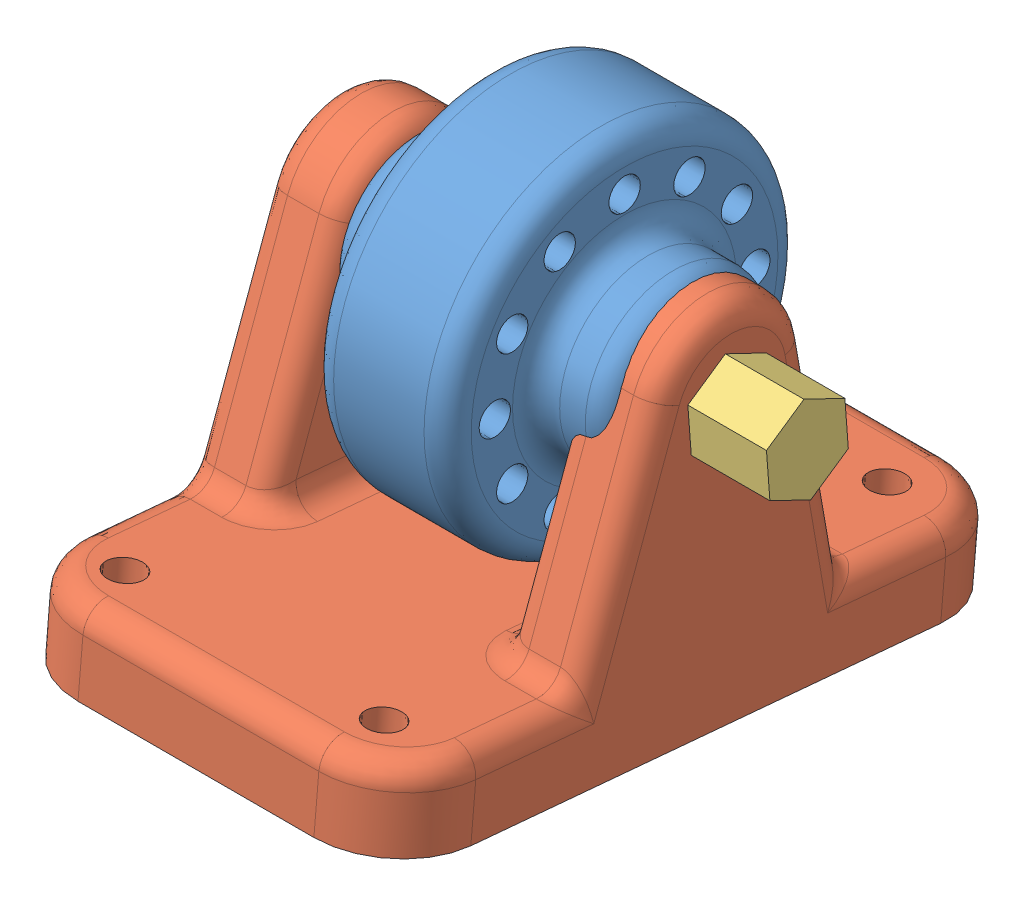
SolidWorks assembly Assem2, configuration Default. Lengths in mm.
Overall size (60 61.02 83.77).
3 component instances, 3 part files, 4 mates.
Components (placement in the parent):
- t7-1: t7 [Default] at (-20.7572 24.5909 48.9887) size (36 45 45)
- T-1: T [Default] at (-15.0072 -6.7591 91.7512) x (0 -0.089597 -0.995978) z (1 0 0) size (80 45.68 50)
- t12-1: t12 [Default] at (19.9928 24.5909 48.9887) x (0 -0.901395 0.432998) z (-1 0 0) size (10 11.55 60)
Mates (geometry in assembly coordinates):
- Concentric1: concentric anti-aligned: circle of t7-1; circle of T-1
- Coincident2: coincident anti-aligned: plane of t7-1 through (-30.0072 32.8409 48.9887) normal (-1 0 0); plane of T-1 through (-30.0072 25.1945 48.7152) normal (1 0 0)
- Concentric2: concentric anti-aligned: circle of T-1; circle of t12-1
- Coincident3: coincident anti-aligned: plane of T-1 through (9.9928 -6.7591 91.7512) normal (1 0 0); plane of t12-1 through (9.9928 24.5909 48.9887) normal (-1 0 0)
